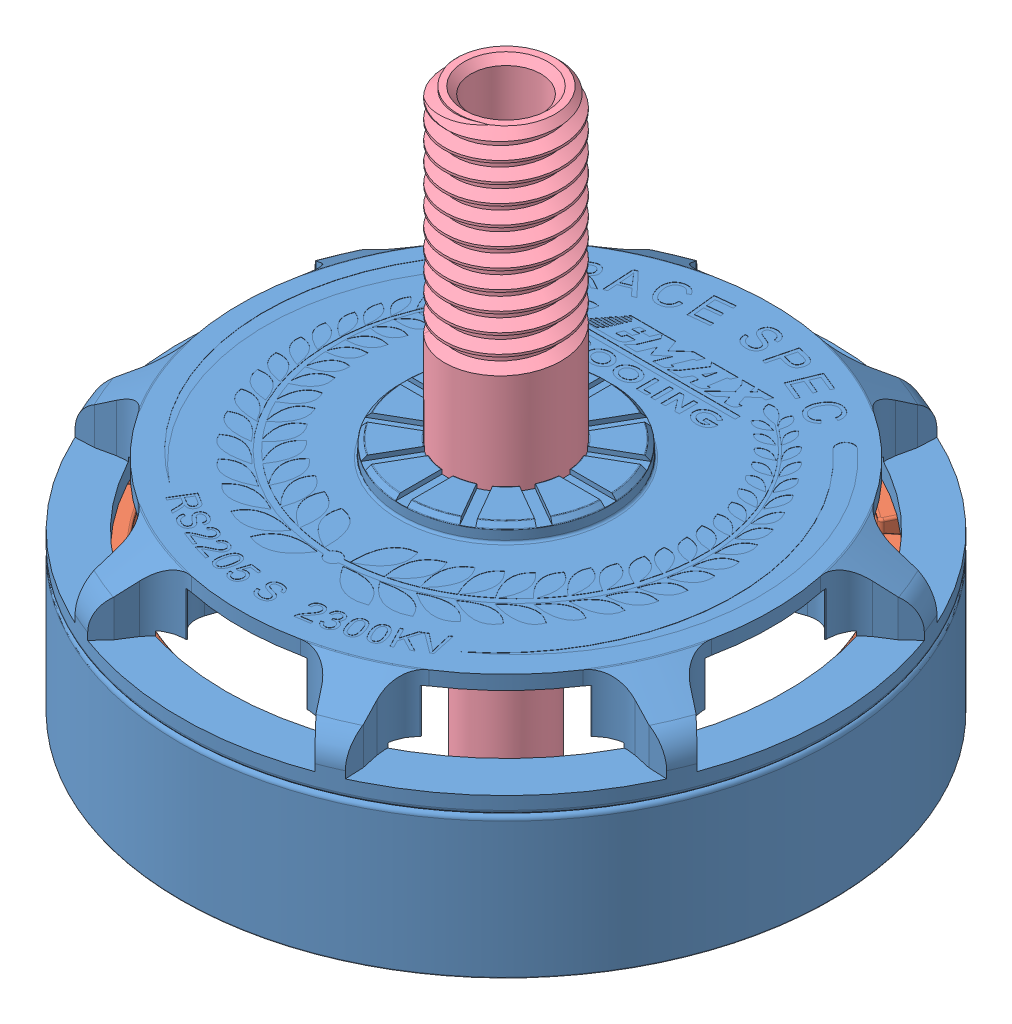
SolidWorks assembly ROTOR, configuration Predeterminado. Lengths in mm.
Overall size (27.91 28.74 27.91).
4 component instances, 4 part files, 9 mates.
Components (placement in the parent):
- ROTOR BELL-1: ROTOR BELL [Predeterminado] at origin size (27.91 10.2 27.91)
- MAGNETS-1: MAGNETS [Predeterminado] at (0 5.3 0) size (25.73 6 25.8)
- MAGNETS ADHESIVE-1: MAGNETS ADHESIVE [Predeterminado] at (0 5.4 0) size (26 5.9 26)
- SHAFT-1: SHAFT [Predeterminado] at (0 0.2 0) size (7.2 28.74 7.2)
Mates (geometry in assembly coordinates):
- Coincidente1: coincident: plane of ROTOR BELL-1 through (0 0 0) normal (0 0 1); plane of assembly through (0 0 0) normal (0 0 1)
- Coincidente2: coincident: plane of ROTOR BELL-1 through (0 0 0) normal (0 1 0); plane of assembly through (0 0 0) normal (0 1 0)
- Coincidente3: coincident: plane of ROTOR BELL-1 through (0 0 0) normal (1 0 0); plane of assembly through (0 0 0) normal (1 0 0)
- Concéntrica1: concentric: cylinder of ROTOR BELL-1 through (0 0 0) axis (0 -1 0) radius 13; cylinder of MAGNETS-1 through (0 11.3 0) axis (0 -1 0) radius 12.9
- Coincidente4: coincident: plane of ROTOR BELL-1 through (-13 11.3 0) normal (0 -1 0); plane of MAGNETS-1 through (3.697 11.3 11.9408) normal (0 1 0)
- Concéntrica2: concentric: cylinder of ROTOR BELL-1 through (0 0 0) axis (0 -1 0) radius 13; cylinder of MAGNETS ADHESIVE-1 through (0 11.3 0) axis (0 -1 0) radius 13
- Coincidente5: coincident: plane of ROTOR BELL-1 through (-13 11.3 0) normal (0 -1 0); plane of MAGNETS ADHESIVE-1 through (0 11.3 0) normal (0 1 0)
- Concéntrica3: concentric: cylinder of ROTOR BELL-1 through (0 0 0) axis (0 -1 0) radius 2.5; cylinder of SHAFT-1 through (0 0.2 0) axis (0 -1 0) radius 2.5
- Coincidente6: coincident: plane of ROTOR BELL-1 through (-2.5 11.65 0) normal (0 -1 0); plane of SHAFT-1 through (2.5 11.65 0) normal (0 1 0)
